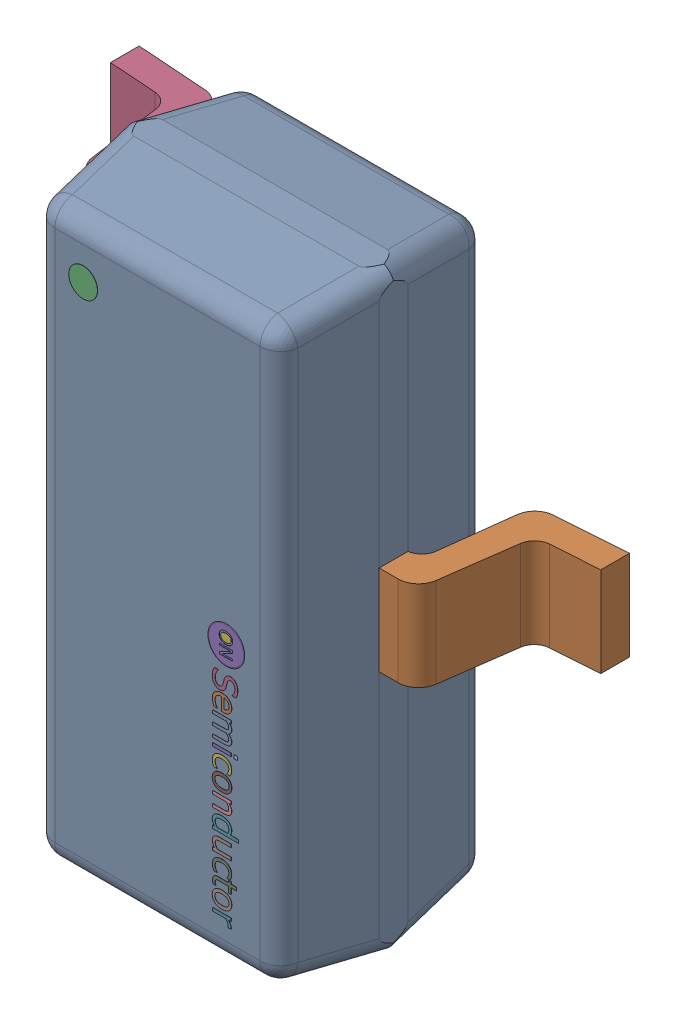
SolidWorks assembly Q3.step, configuration Default. Lengths in mm.
Overall size (2.4 2.9 1.11).
5 component instances, 4 part files, 0 mates.
Components (placement in the parent):
- IC_ON_Semiconductor_NUD3112LT1G_eec.step-1: IC_ON_Semiconductor_NUD3112LT1G_eec.step [Default] at (17.919 17.272 0) size (2.4 2.9 1.11)
  - 1-5.step-1: 1-5.step [Default] at (0 0 0.1) x (0 1 0) z (0 0 1) size (2.9 1.3 1.01)
  - 2-6.step-1: 2-6.step [Default] x (-1 0 0) z (0 1 0) size (2.4 0.68 2.34)
  - ON Semi Logo - withoutPN.step-1: ON Semi Logo - withoutPN.step [Default] at (-0.2581 -0.9018 1.011) x (-1 0 0) z (0 0 1) size (0.19 0.19 0.1)
  - ON Semi Logo - withoutPN - Copy.step-1: ON Semi Logo - withoutPN - Copy.step [Default] at (-0.2645 -0.8914 1.011) x (-1 0 0) z (0 0 1) size (0.83 2.45 0.1)
